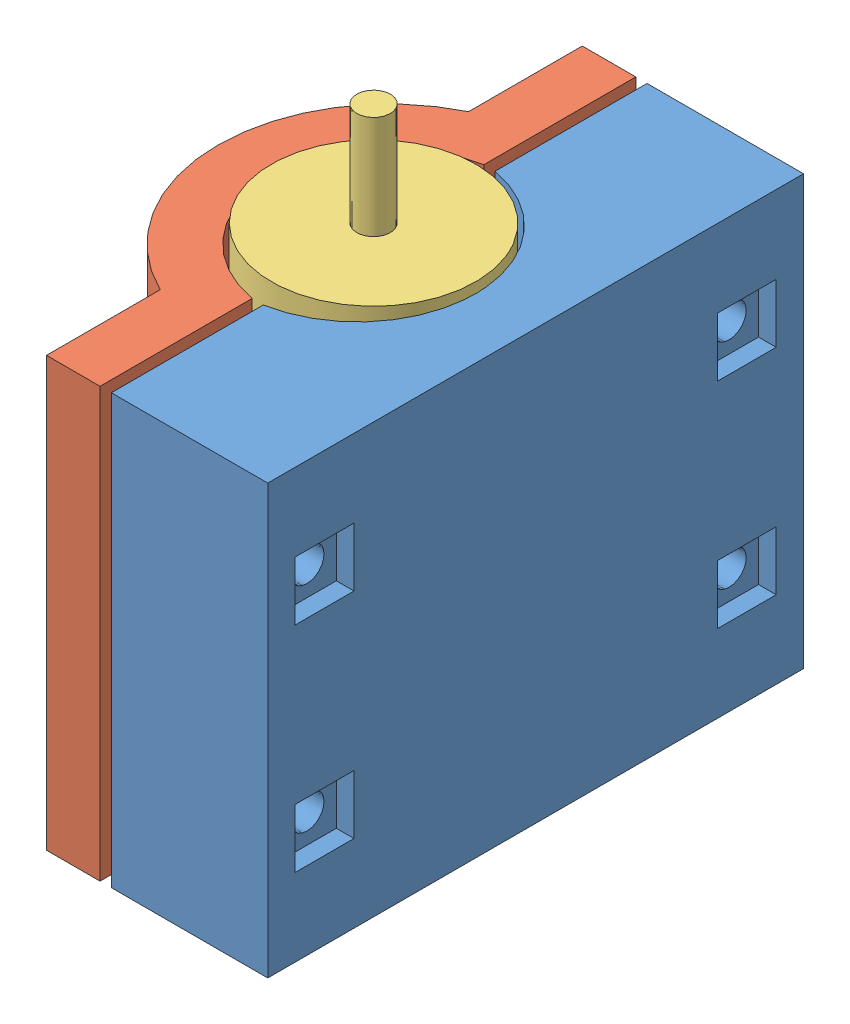
SolidWorks assembly Assem1, configuration Default. Lengths in mm.
Overall size (37.66 64.25 63.5).
3 component instances, 3 part files, 5 mates.
Components (placement in the parent):
- motor_mount half base-1: motor_mount half base [Default] at (8.9529 4.9475 71.3885) size (18.54 50.8 63.5)
- motor_mount half-1: motor_mount half [Default] at (7.6194 4.9475 39.6385) x (-1 0 0) z (0 0 -1) size (17.78 50.8 63.5)
- motor-1: motor [Default] at (8.2861 4.9475 39.6385) x (-0.43263 0 -0.901572) z (0.901572 0 -0.43263) size (24.19 64.25 24.19)
Mates (geometry in assembly coordinates):
- Coincident2: coincident aligned: plane of motor_mount half base-1 through (8.9529 55.7475 71.3885) normal (0 1 0); plane of motor_mount half-1 through (7.6194 55.7475 39.6385) normal (0 1 0)
- Coincident3: coincident aligned: plane of motor_mount half base-1 through (8.9529 121.8993 71.3885) normal (0 0 1); plane of motor_mount half-1 through (7.6194 121.6897 71.3885) normal (0 0 1)
- Coincident4: coincident aligned: plane of motor_mount half base-1 through (8.9529 4.9475 71.3885) normal (0 -1 0); plane of motor-1 through (8.2861 4.9475 39.6385) normal (0 -1 0)
- Tangent1: tangent aligned: cylinder of motor_mount half base-1 through (6.4129 -26.2904 39.6385) axis (0 1 0) radius 13.97; cylinder of motor-1 through (8.2861 91.1815 39.6385) axis (0 -1 0) radius 12.0968
- Tangent2: tangent aligned: cylinder of motor_mount half-1 through (10.1594 121.6897 39.6385) axis (0 -1 0) radius 13.97; cylinder of motor-1 through (8.2861 91.1815 39.6385) axis (0 -1 0) radius 12.0968
